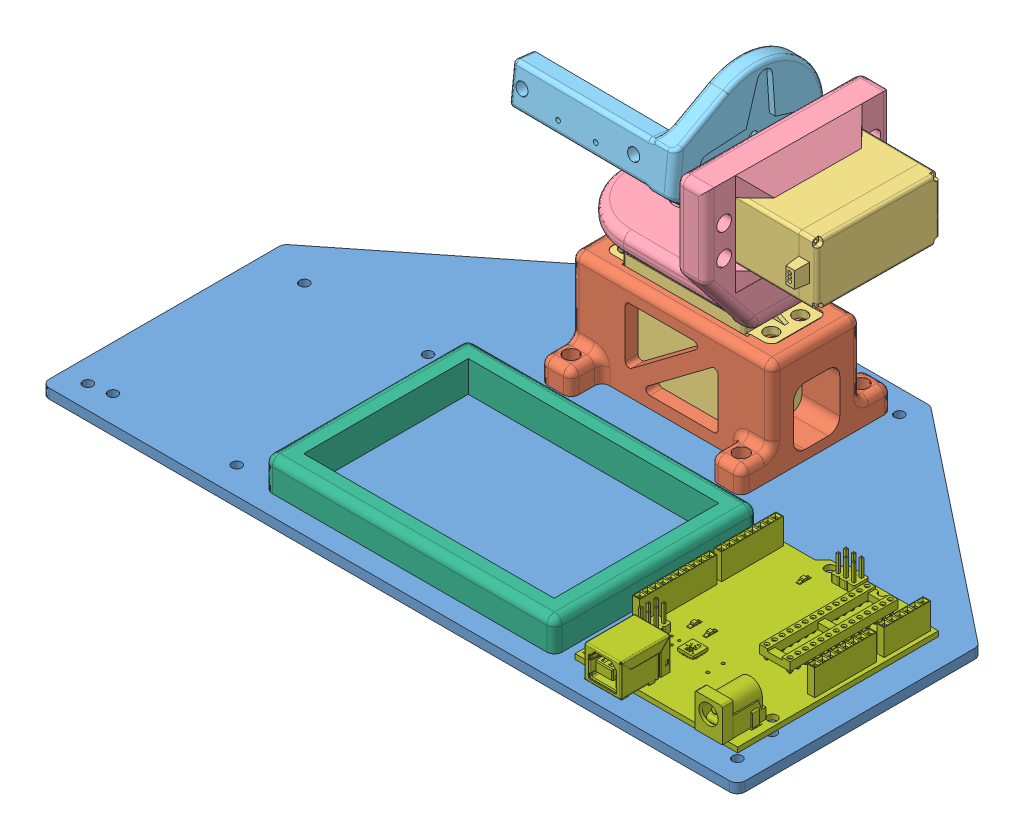
SolidWorks assembly Pan-Tilt Mechanism, configuration Default. Lengths in mm.
Overall size (228.6 108.58 139.7).
8 component instances, 7 part files, 19 mates.
Components (placement in the parent):
- Pan-Tilt Base-1: Pan-Tilt Base [Default] at (-115.4444 -2.3346 91.4179) size (228.6 3.17 139.7)
- Pan Servo Mount-1: Pan Servo Mount [Default] at (-1.1444 0.8404 -15.8971) size (66.04 32.38 49.53)
- Servo-1: Servo [Default] at (-1.7283 -2.7555 -15.6471) size (55.4 47.6 20)
- Tilt Base2-1: Tilt Base2 [Default] at (-10.7431 45.9675 -15.6471) x (0.999962 0 0.008671) z (-0.008671 0 0.999962) size (73.96 51.99 60.24)
- Servo-2: Servo [Default] at (62.29 81.2695 -5.7981) x (-0.008671 0 0.999962) z (0 -1 0) size (55.4 47.6 20)
- Sensor Holder-1: Sensor Holder [Default] at (-18.3432 84.3621 12.3336) x (-0.999962 0 -0.008671) z (0.008618 -0.110387 -0.993851) size (53.98 43.18 49.61)
- Breadboard Mount-1: Breadboard Mount [Default] at (-1.1444 0.8404 51.4129) size (95.25 10.16 66.8)
- arduino uno-1: arduino uno [Default] at (106.5029 4.9904 84.6401) x (0.999998 0 -0.001956) z (0.001956 0 0.999998) size (53.34 15.25 74.93)
Mates (geometry in assembly coordinates):
- Coincident1: coincident anti-aligned: plane of Pan-Tilt Base-1 through (-115.4444 0.8404 91.4179) normal (0 1 0); plane of Pan Servo Mount-1 through (-1.1444 0.8404 -15.8971) normal (0 -1 0)
- Coincident2: coincident anti-aligned: plane of Pan Servo Mount-1 through (-26.0364 30.6854 -9.2296) normal (0 1 0); plane of Servo-1 through (-29.4283 30.6854 -6.6471) normal (0 -1 0)
- Concentric4: concentric aligned: cylinder of Pan Servo Mount-1 through (-25.4444 20.5254 -10.8971) axis (0 1 0) radius 2.413; cylinder of Servo-1 through (-25.4444 24.3215 -10.8971) axis (0 1 0) radius 2.25
- Parallel1: parallel aligned: plane of Pan Servo Mount-1 through (-34.1644 33.2254 -30.5021) normal (0 0 -1); plane of Servo-1 through (-21.7283 36.7445 -25.6471) normal (0 0 -1)
- Coincident3: coincident anti-aligned: plane of Tilt Base2-1 through (28.9302 45.9675 -15.3031) normal (-0.999962 0 -0.008671); plane of Servo-2 through (28.6101 72.2695 21.6109) normal (0.999962 0 0.008671)
- Concentric5: concentric aligned: cylinder of Tilt Base2-1 through (36.6757 86.0195 -29.7372) axis (-0.999962 0 -0.008671) radius 2.413; cylinder of Servo-2 through (35.4197 86.0195 -29.7481) axis (-0.999962 0 -0.008671) radius 2.25
- Parallel2: parallel aligned: plane of Tilt Base2-1 through (-10.7431 97.7835 -15.6471) normal (0 1 0); plane of Servo-2 through (22.9649 91.2695 -26.1399) normal (0 1 0)
- Concentric6: concentric aligned: circle of Servo-2; cylinder of Sensor Holder-1 through (13.647 81.2695 -15.235) axis (-0.999962 0 -0.008671) radius 1.5875
- Concentric7: concentric aligned: circle of Servo-1; cylinder of Tilt Base2-1 through (-10.7431 52.3175 -15.6471) axis (0 -1 0) radius 1.5875
- Distance1: distance = 6.223 mm anti-aligned: plane of Sensor Holder-1 through (13.7402 86.619 -25.9746) normal (0.999962 0 0.008671); plane of Servo-2 through (19.9518 72.5195 -24.637) normal (-0.999962 0 -0.008671)
- Distance2: distance = 6.223 mm anti-aligned: plane of Tilt Base2-1 through (-10.7431 45.9675 -15.6471) normal (0 -1 0); plane of Servo-1 through (-20.1994 39.7445 -6.8971) normal (0 1 0)
- DELETE: parallel: line of Pan-Tilt Base-1 through (-115.4444 0.8404 27.9179) axis (1 0 0); plane of Sensor Holder-1
- Concentric8: concentric aligned: cylinder of Pan-Tilt Base-1 through (26.7956 0.8404 3.7879) axis (0 -1 0) radius 1.778; cylinder of Pan Servo Mount-1 through (26.7956 33.2254 3.7879) axis (0 -1 0) radius 2.3876
- Concentric9: concentric aligned: cylinder of Pan-Tilt Base-1 through (-29.0844 0.8404 -35.5821) axis (0 -1 0) radius 1.778; cylinder of Pan Servo Mount-1 through (-29.0844 33.2254 -35.5821) axis (0 -1 0) radius 2.3876
- Coincident5: coincident anti-aligned: plane of Pan-Tilt Base-1 through (-115.4444 0.8404 91.4179) normal (0 1 0); plane of Breadboard Mount-1 through (-1.1444 0.8404 51.4129) normal (0 -1 0)
- Concentric10: concentric anti-aligned: circle of Pan-Tilt Base-1; cylinder of Breadboard Mount-1 through (-45.5944 8.4604 81.8929) axis (0 -1 0) radius 1.9939
- Concentric11: concentric anti-aligned: cylinder of Pan-Tilt Base-1 through (43.3056 -2.3346 20.9329) axis (0 1 0) radius 1.524; cylinder of Breadboard Mount-1 through (43.3056 8.4604 20.9329) axis (0 -1 0) radius 1.8669
- Concentric13: concentric aligned: circle of Pan-Tilt Base-1; circle of arduino uno-1
- Coincident10: coincident anti-aligned: plane of Pan-Tilt Base-1 through (-115.4444 0.8404 91.4179) normal (0 1 0); plane of arduino uno-1 through (62.2334 0.8404 79.7966) normal (0 -1 0)
